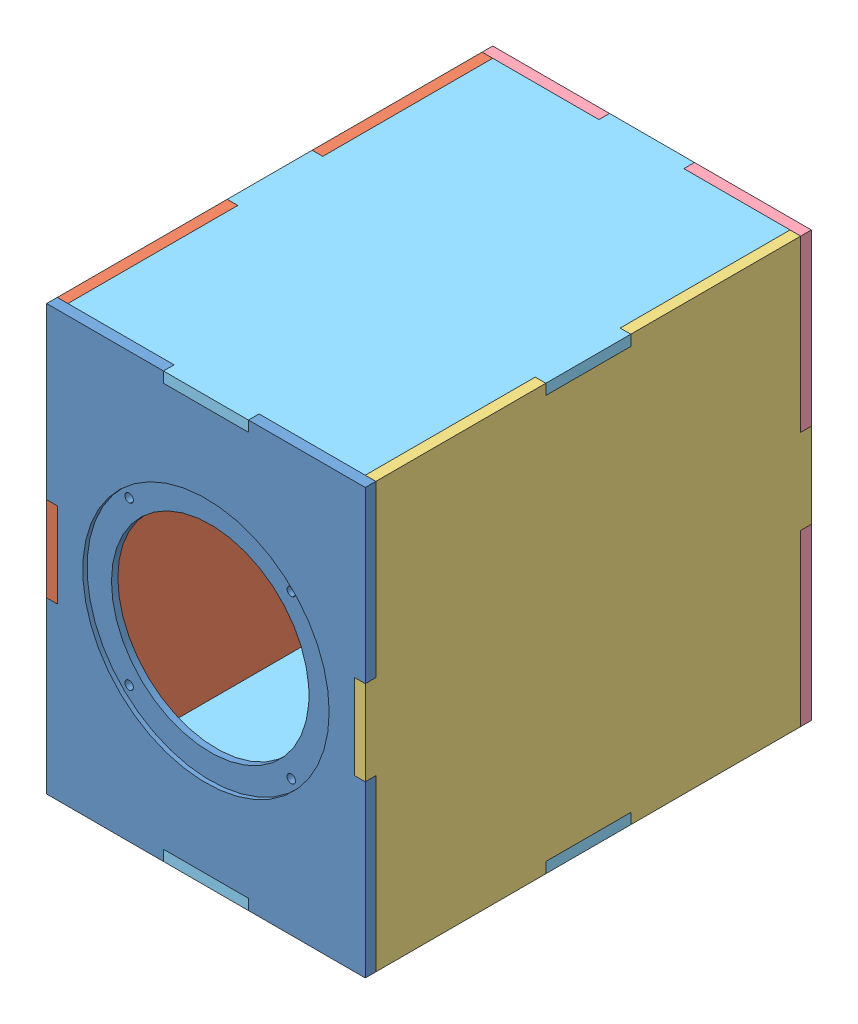
SolidWorks assembly Subwoofer_Caja, configuration Predeterminado. Lengths in mm.
Overall size (150 200 210).
6 component instances, 5 part files, 15 mates.
Components (placement in the parent):
- Front-1: Front [Predeterminado] at (-16.365 -0.3836 197.5) size (150 200 5)
- Left-1: Left [Predeterminado] at (-86.365 -0.3836 97.5) x (0 0 1) z (-1 0 0) size (210 200 5)
- Right-1: Right [Predeterminado] at (53.635 -0.3836 97.5) x (0 0 -1) z (1 0 0) size (210 200 5)
- Back-1: Back [Predeterminado] at (-16.365 -0.3836 -7.5) size (150 200 5)
- Bottom-1: Bottom [Predeterminado] at (-16.365 94.6164 97.5) x (1 0 0) z (0 1 0) size (150 210 5)
- Bottom-2: Bottom [Predeterminado] at (-16.365 -95.3836 97.5) x (1 0 0) z (0 -1 0) size (150 210 5)
Mates (geometry in assembly coordinates):
- Coincidente1: coincident: plane of assembly; plane of assembly; plane of Front-1 through (-86.365 -20.3836 197.5) normal (-1 0 0); plane of Left-1 through (-86.365 -0.3836 97.5) normal (1 0 0)
- Coincidente3: coincident: plane of assembly; plane of assembly; plane of Front-1 through (-16.365 -0.3836 197.5) normal (0 0 -1); plane of Left-1 through (-91.365 -100.3836 197.5) normal (0 0 1)
- Coincidente4: coincident: plane of assembly; plane of assembly; plane of Front-1 through (-91.365 99.6164 202.5) normal (0 1 0); plane of Left-1 through (-91.365 99.6164 117.5) normal (0 1 0)
- Coincidente5: coincident: plane of assembly; plane of assembly; plane of Front-1 through (53.635 -20.3836 197.5) normal (1 0 0); plane of Right-1 through (53.635 -0.3836 97.5) normal (-1 0 0)
- Coincidente6: coincident: plane of assembly; plane of assembly; plane of Front-1 through (-91.365 99.6164 202.5) normal (0 1 0); plane of Right-1 through (58.635 99.6164 197.5) normal (0 1 0)
- Coincidente7: coincident: plane of assembly; plane of assembly; plane of Front-1 through (-16.365 -0.3836 197.5) normal (0 0 -1); plane of Right-1 through (58.635 19.6164 197.5) normal (0 0 1)
- Coincidente8: coincident: plane of assembly; plane of assembly; plane of Right-1 through (58.635 19.6164 -2.5) normal (0 0 -1); plane of Back-1 through (-16.365 -0.3836 -2.5) normal (0 0 1)
- Coincidente9: coincident: plane of assembly; plane of assembly; plane of Right-1 through (58.635 99.6164 77.5) normal (0 1 0); plane of Back-1 through (-91.365 99.6164 -2.5) normal (0 1 0)
- Coincidente10: coincident: plane of assembly; plane of assembly; plane of Right-1 through (58.635 -0.3836 97.5) normal (1 0 0); plane of Back-1 through (58.635 -100.3836 -2.5) normal (1 0 0)
- Coincidente11: coincident: plane of assembly; plane of assembly; plane of Back-1 through (3.635 94.6164 -7.5) normal (0 1 0); plane of Bottom-1 through (-16.365 94.6164 97.5) normal (0 -1 0)
- Coincidente12: coincident: plane of assembly; plane of assembly; plane of Right-1 through (58.635 -0.3836 97.5) normal (1 0 0); plane of Bottom-1 through (58.635 99.6164 117.5) normal (1 0 0)
- Coincidente13: coincident: plane of assembly; plane of assembly; plane of Front-1 through (-16.365 -0.3836 202.5) normal (0 0 1); plane of Bottom-1 through (-36.365 99.6164 202.5) normal (0 0 1)
- Coincidente14: coincident: plane of assembly; plane of assembly; plane of Front-1 through (3.635 -95.3836 197.5) normal (0 -1 0); plane of Bottom-2 through (-16.365 -95.3836 97.5) normal (0 1 0)
- Coincidente15: coincident: plane of assembly; plane of assembly; plane of Right-1 through (53.635 -0.3836 97.5) normal (-1 0 0); plane of Bottom-2 through (53.635 -100.3836 117.5) normal (1 0 0)
- Coincidente16: coincident: plane of assembly; plane of assembly; plane of Front-1 through (-16.365 -0.3836 202.5) normal (0 0 1); plane of Bottom-2 through (-36.365 -100.3836 202.5) normal (0 0 1)
